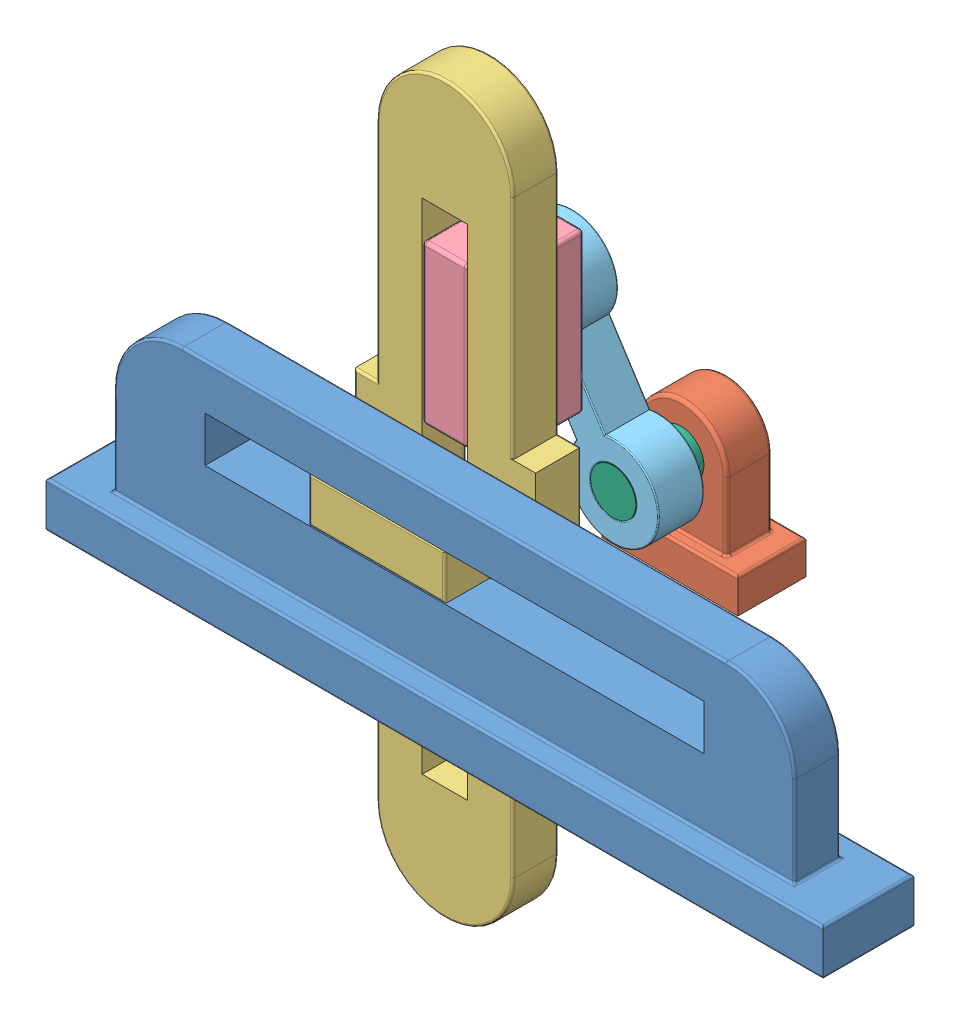
SolidWorks assembly SliderCrank, configuration Default. Lengths in mm.
Overall size (342.57 320 135).
6 component instances, 6 part files, 14 mates.
Components (placement in the parent):
- Slider Body-2: Slider Body [Default] at (60 35 -10) x (1 0 0) z (0 -1 0) size (342.57 40 90)
- Rotor-2: Rotor [Default] at (140 15 -85) x (1 0 0) z (0 -1 0) size (60 30 65)
- Slider-1: Slider [Default] at (135.8147 175 -40) size (80 320 50)
- Connector-2: Connector [Default] at (157.1481 103.8832 -60) x (-1 0 0) z (0 0 -1) size (50 70 60)
- Connecting-rod-1: Connecting-rod [Default] at (132.1481 103.8832 -70) x (0.841189 0.540742 0) z (0 0 1) size (40 110 20)
- Connecting-Pin-1: Connecting-Pin [Default] at (170 45 -110) x (1 0 0) z (0 -1 0) size (20 50 20)
Mates (geometry in assembly coordinates):
- Coincident2: coincident: plane of Slider Body-2 through (60 35 0) normal (0 0 -1); plane of assembly through (0 0 0) normal (0 0 1)
- Coincident3: coincident: plane of Slider Body-2 through (60 0 -10) normal (0 1 0); plane of assembly through (0 0 0) normal (0 1 0)
- Coincident4: coincident: plane of Slider Body-2 through (0 -15 20) normal (-1 0 0); plane of assembly through (0 0 0) normal (1 0 0)
- Coincident15: coincident: plane of Rotor-2 through (140 0 -85) normal (0 -1 0); plane of assembly through (0 0 0) normal (0 1 0)
- Coincident16: coincident: plane of Slider Body-2 through (170 35 -10) normal (-1 0 0); axis of Rotor-2 through (170 45 -91.5) axis (0 0 -1)
- Coincident17: coincident: plane of Slider Body-2 through (50 45 10) normal (0 0 1); plane of Slider-1 through (135.8147 175 10) normal (0 0 1)
- Coincident18: coincident: plane of Slider Body-2 through (60 55 10) normal (0 -1 0); plane of Slider-1 through (105.8147 55 10) normal (0 1 0)
- Coincident21: coincident: plane of Slider-1 through (135.8147 175 -20) normal (0 0 1); plane of Connector-2 through (145.8147 138.8832 -20) normal (0 0 1)
- Coincident22: coincident: plane of Slider-1 through (125.8147 -65 -20) normal (1 0 0); plane of Connector-2 through (125.8147 138.8832 -20) normal (-1 0 0)
- Coincident23: coincident: plane of Connector-2 through (132.1481 103.8832 -80) normal (0 0 -1); plane of Connecting-rod-1 through (132.1481 103.8832 -80) normal (0 0 -1)
- Concentric1: concentric: cylinder of Connector-2 through (132.1481 103.8832 -80) axis (0 0 1) radius 10; cylinder of Connecting-rod-1 through (132.1481 103.8832 -60) axis (0 0 -1) radius 10
- Coincident24: coincident: plane of Connecting-rod-1 through (132.1481 103.8832 -60) normal (0 0 1); plane of Connecting-Pin-1 through (170 45 -60) normal (0 0 1)
- Concentric2: concentric: cylinder of Connecting-rod-1 through (170 45 -60) axis (0 0 -1) radius 10; cylinder of Connecting-Pin-1 through (170 45 -60) axis (0 0 -1) radius 10
- Concentric3: concentric: cylinder of Rotor-2 through (170 45 -90) axis (0 0 -1) radius 10; cylinder of Connecting-Pin-1 through (170 45 -60) axis (0 0 -1) radius 10
